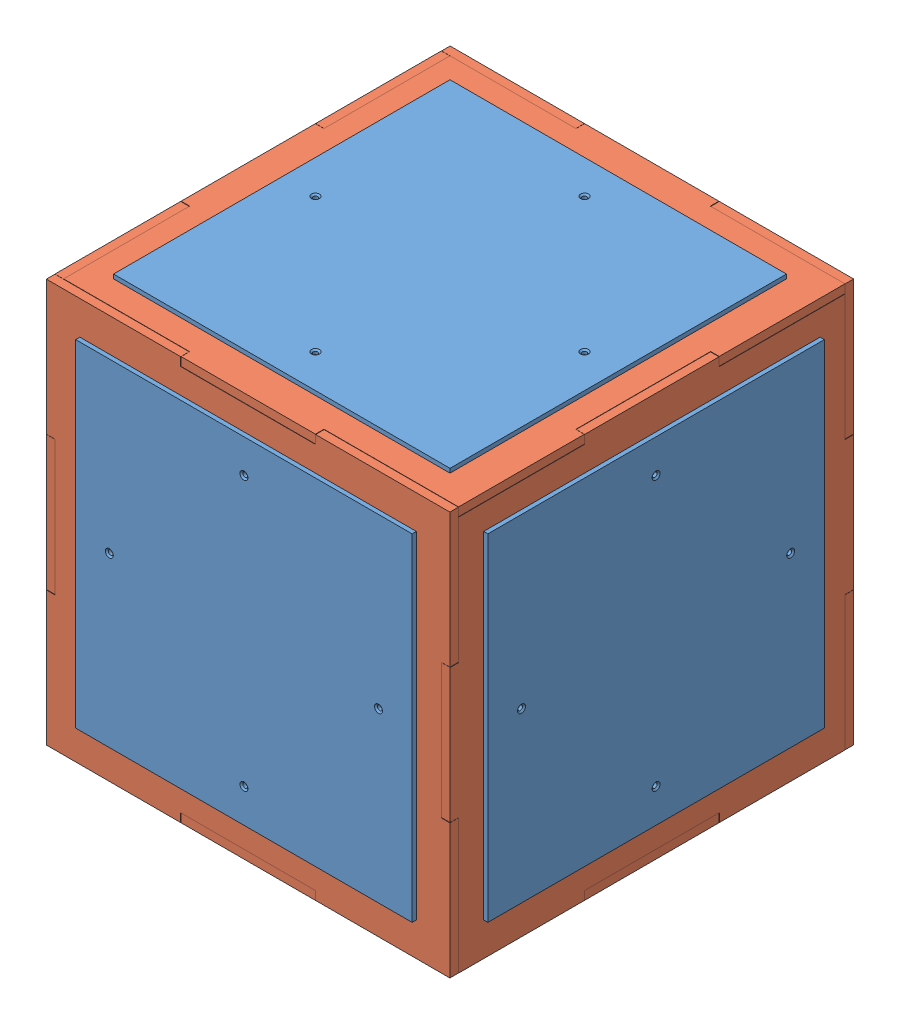
SolidWorks assembly master_acrylic_cube, configuration master_cube. Lengths in mm.
Overall size (155.57 155.57 155.57).
12 component instances, 2 part files, 6 mates.
Components (placement in the parent):
- panel^master_acrylic_cube-2: panel^master_acrylic_cube [cube01] x (-1 0 0) z (0 0 1) size (127 1.59 127) (virtual)
- acrylic_panel^master_acrylic_cube-1: acrylic_panel^master_acrylic_cube [A] at origin size (152.3 3.23 152.3) (virtual)
- panel^master_acrylic_cube-8: panel^master_acrylic_cube [cube01] x (0 -1 0) z (0 0 1) size (127 1.59 127) (virtual)
- panel^master_acrylic_cube-9: panel^master_acrylic_cube [cube01] at origin size (127 1.59 127) (virtual)
- panel^master_acrylic_cube-10: panel^master_acrylic_cube [cube01] x (0 1 0) z (0 0 1) size (127 1.59 127) (virtual)
- panel^master_acrylic_cube-11: panel^master_acrylic_cube [cube01] x (-1 0 0) z (0 -1 0) size (127 1.59 127) (virtual)
- panel^master_acrylic_cube-12: panel^master_acrylic_cube [cube01] x (-1 0 0) z (0 1 0) size (127 1.59 127) (virtual)
- acrylic_panel^master_acrylic_cube-23: acrylic_panel^master_acrylic_cube [A] x (0 1 0) z (0 0 1) size (152.3 3.23 152.3) (virtual)
- acrylic_panel^master_acrylic_cube-24: acrylic_panel^master_acrylic_cube [A] x (-1 0 0) z (0 0 1) size (152.3 3.23 152.3) (virtual)
- acrylic_panel^master_acrylic_cube-25: acrylic_panel^master_acrylic_cube [A] x (0 -1 0) z (0 0 1) size (152.3 3.23 152.3) (virtual)
- acrylic_panel^master_acrylic_cube-26: acrylic_panel^master_acrylic_cube [B] x (1 0 0) z (0 -1 0) size (152.3 3.23 152.3) (virtual)
- acrylic_panel^master_acrylic_cube-27: acrylic_panel^master_acrylic_cube [B] x (1 0 0) z (0 1 0) size (152.3 3.23 152.3) (virtual)
Mates (geometry in assembly coordinates):
- Coincident1: coincident aligned: plane of panel^master_acrylic_cube-2 through (0 0 0) normal (0 0 1); plane of assembly through (0 0 0) normal (0 0 1)
- Coincident2: coincident anti-aligned: plane of panel^master_acrylic_cube-2; plane of assembly through (0 0 0) normal (1 0 0)
- Coincident3: coincident anti-aligned: plane of panel^master_acrylic_cube-2; plane of assembly through (0 0 0) normal (0 1 0)
- Coincident4: coincident aligned: plane of acrylic_panel^master_acrylic_cube-1 through (0 0 0) normal (0 0 1); plane of assembly through (0 0 0) normal (0 0 1)
- Coincident5: coincident aligned: plane of acrylic_panel^master_acrylic_cube-1 through (0 0 0) normal (1 0 0); plane of assembly through (0 0 0) normal (1 0 0)
- Coincident6: coincident aligned: plane of ? through (0 0 0) normal (0 1 0); plane of assembly through (0 0 0) normal (0 1 0)
